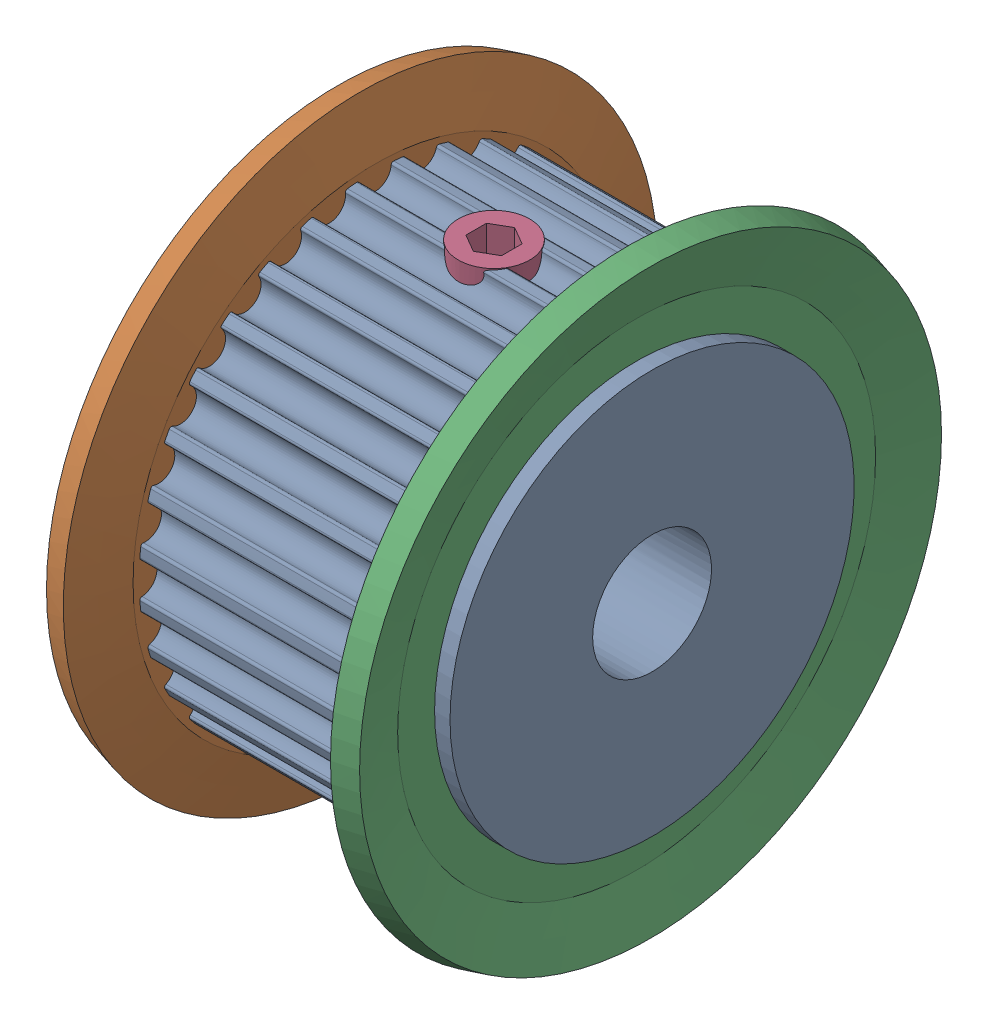
SolidWorks assembly Timing pulley_GPA32GT2090-A-P5_MISUMI, configuration Default. Lengths in mm.
Overall size (13.3 25 25).
5 component instances, 3 part files, 12 mates.
Components (placement in the parent):
- Timing Pulley_Timing pulley_GPA32GT2090-A-P5_MISUMI-1: Timing Pulley_Timing pulley_GPA32GT2090-A-P5_MISUMI [Default] at origin size (13.3 19.83 19.8)
- Flange_Timing pulley_GPA32GT2090-A-P5_MISUMI-1: Flange_Timing pulley_GPA32GT2090-A-P5_MISUMI [Default] at (0.65 0 0) size (1.59 25 25)
- Flange_Timing pulley_GPA32GT2090-A-P5_MISUMI-2: Flange_Timing pulley_GPA32GT2090-A-P5_MISUMI [Default] at (12.65 0 0) x (-1 0 0) z (0 0 -1) size (1.59 25 25)
- Set Screw-1_Timing pulley_GPA32GT2090-A-P5_MISUMI-1: Set Screw-1_Timing pulley_GPA32GT2090-A-P5_MISUMI [Default] at (6.65 6.93 0) size (3 3 3)
- Set Screw-1_Timing pulley_GPA32GT2090-A-P5_MISUMI-2: Set Screw-1_Timing pulley_GPA32GT2090-A-P5_MISUMI [Default] at (6.65 -3.465 -6.0016) x (1 0 0) z (0 0.866025 -0.5) size (3 3 3)
Mates (geometry in assembly coordinates):
- Concentric1: concentric anti-aligned: cylinder of Timing Pulley_BaseModel20220429154339-1 through (0 0 0) axis (-1 0 0) radius 8.5; cylinder of Flange_BaseModel20220429154339-1 through (1.65 0 0) axis (1 0 0) radius 8.5
- Coincident1: coincident anti-aligned: plane of Timing Pulley_BaseModel20220429154339-1 through (1.65 8.5 0) normal (-1 0 0); plane of Flange_BaseModel20220429154339-1 through (1.65 8.5 0) normal (1 0 0)
- Coincident2: coincident aligned: plane of Timing Pulley_BaseModel20220429154339-1 through (0 0 0) normal (0 0 1); plane of Flange_BaseModel20220429154339-1 through (0.65 0 0) normal (0 0 1)
- Concentric2: concentric aligned: cylinder of Timing Pulley_BaseModel20220429154339-1 through (0 0 0) axis (-1 0 0) radius 8.5; cylinder of Flange_BaseModel20220429154339-2 through (11.65 0 0) axis (-1 0 0) radius 8.5
- Coincident3: coincident anti-aligned: plane of Timing Pulley_BaseModel20220429154339-1 through (11.65 8.5 0) normal (1 0 0); plane of Flange_BaseModel20220429154339-2 through (11.65 8.5 0) normal (-1 0 0)
- Coincident4: coincident anti-aligned: plane of Timing Pulley_BaseModel20220429154339-1 through (0 0 0) normal (0 0 1); plane of Flange_BaseModel20220429154339-2 through (12.65 0 0) normal (0 0 -1)
- Concentric3: concentric aligned: cylinder of Timing Pulley_BaseModel20220429154339-1 through (6.65 9.93 0) axis (0 1 0) radius 1.25; cylinder of Set Screw-1_BaseModel20220429154339-1 through (6.65 9.93 0) axis (0 1 0) radius 1.5
- Tangent1: tangent aligned: cylinder of Timing Pulley_BaseModel20220429154339-1 through (0 0 0) axis (-1 0 0) radius 9.93; plane of Set Screw-1_BaseModel20220429154339-1 through (6.65 9.93 0) normal (0 1 0)
- Concentric4: concentric aligned: cylinder of Timing Pulley_BaseModel20220429154339-1 through (6.65 -4.965 -8.5996) axis (0 -0.5 -0.866025) radius 1.25; cylinder of Set Screw-1_BaseModel20220429154339-2 through (6.65 -4.965 -8.5996) axis (0 -0.5 -0.866025) radius 1.5
- Tangent2: tangent aligned: cylinder of Timing Pulley_BaseModel20220429154339-1 through (0 0 0) axis (-1 0 0) radius 9.93; plane of Set Screw-1_BaseModel20220429154339-2 through (6.65 -4.965 -8.5996) normal (0 -0.5 -0.866025)
- Parallel1: parallel aligned: plane of Timing Pulley_BaseModel20220429154339-1 through (0 0 0) normal (1 0 0); plane of Set Screw-1_BaseModel20220429154339-1 through (6.65 6.93 0) normal (1 0 0)
- Parallel2: parallel aligned: plane of Timing Pulley_BaseModel20220429154339-1 through (0 0 0) normal (1 0 0); plane of Set Screw-1_BaseModel20220429154339-2 through (6.65 -3.465 -6.0016) normal (1 0 0)
